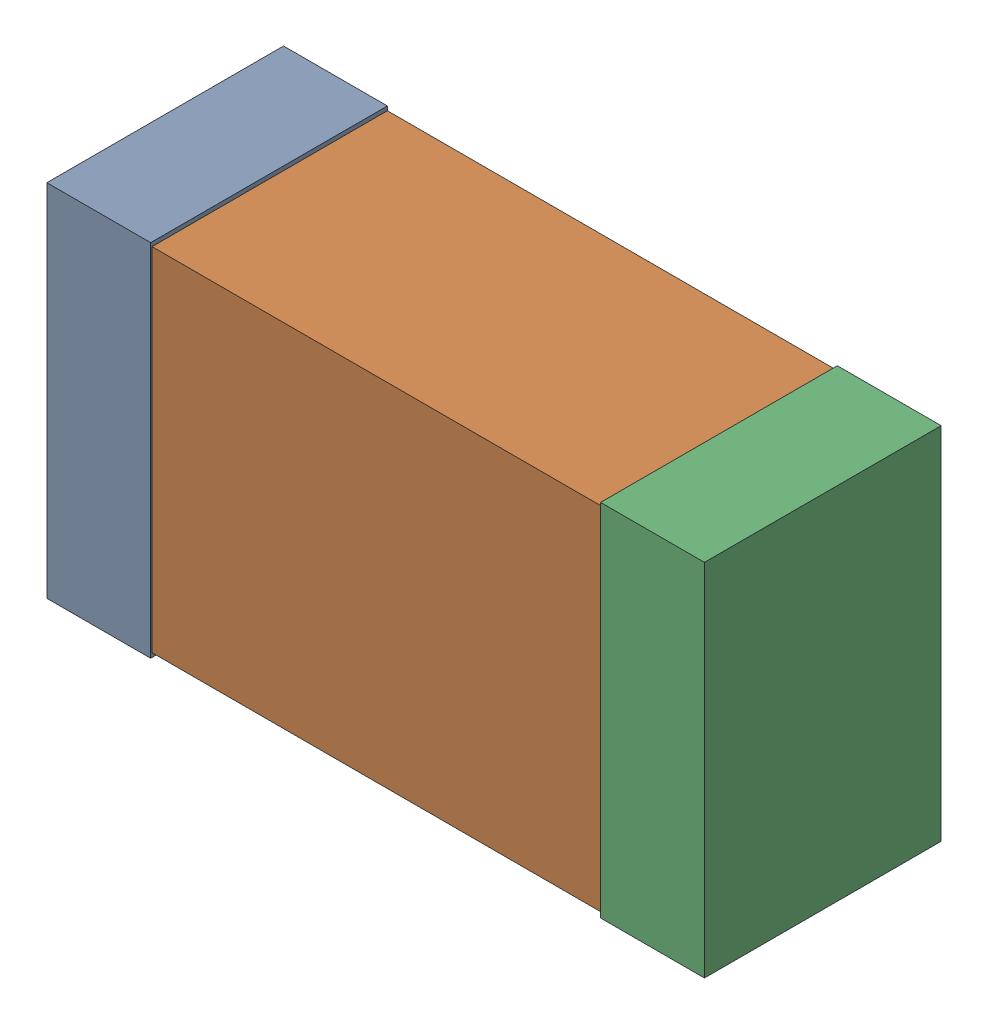
SolidWorks assembly C9_Motor_8Kanaloa_v2.0.0_Motor, configuration Default. Lengths in mm.
Overall size (2.38 1.3 0.85).
6 component instances, 2 part files, 0 mates.
Components (placement in the parent):
- 352877648-1: 352877648 [Default] at (119.349 132.969 0) size (0.38 1.3 0.85)
  - Extruded_14-1: Extruded_14 [Default] at origin size (0.38 1.3 0.85)
- 352877392-1: 352877392 [Default] at (120.349 132.969 0) size (2.2 1.27 0.85)
  - Extruded_15-1: Extruded_15 [Default] at origin size (2.2 1.27 0.85)
- 352877648-2: 352877648 [Default] at (121.349 132.969 0) size (0.38 1.3 0.85)
  - Extruded_14-1: Extruded_14 [Default] at origin size (0.38 1.3 0.85)
